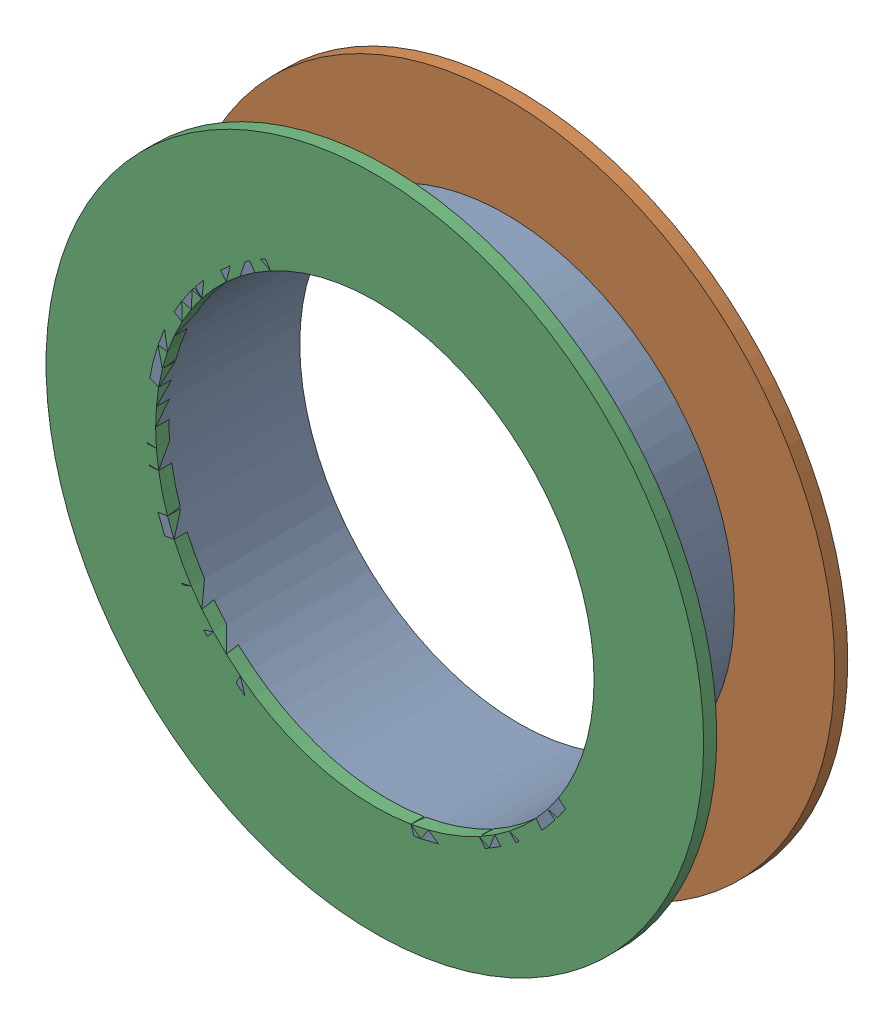
SolidWorks assembly Pad U1-1(13.758mm,59.438mm) on Multi-Layer, configuration Predeterminado. Lengths in mm.
Overall size (1.79 1.79 0.39).
6 component instances, 2 part files, 0 mates.
Components (placement in the parent):
- Pad Hole-1: Pad Hole [Predeterminado] at (13.7584 59.4378 -0.4013) size (1.24 1.24 0.39)
  - Pad Hole-Part-1-1: Pad Hole-Part-1 [Predeterminado] at origin size (1.24 1.24 0.39)
- Top Layer-1: Top Layer [Predeterminado] at (13.7584 59.4378 -0.4013) size (1.79 1.79 0.04)
  - Top Layer-Part-1-1: Top Layer-Part-1 [Predeterminado] at origin size (1.79 1.79 0.04)
- Top Layer-2: Top Layer [Predeterminado] at (13.7584 59.4378 -0.0457) size (1.79 1.79 0.04)
  - Top Layer-Part-1-1: Top Layer-Part-1 [Predeterminado] at origin size (1.79 1.79 0.04)
